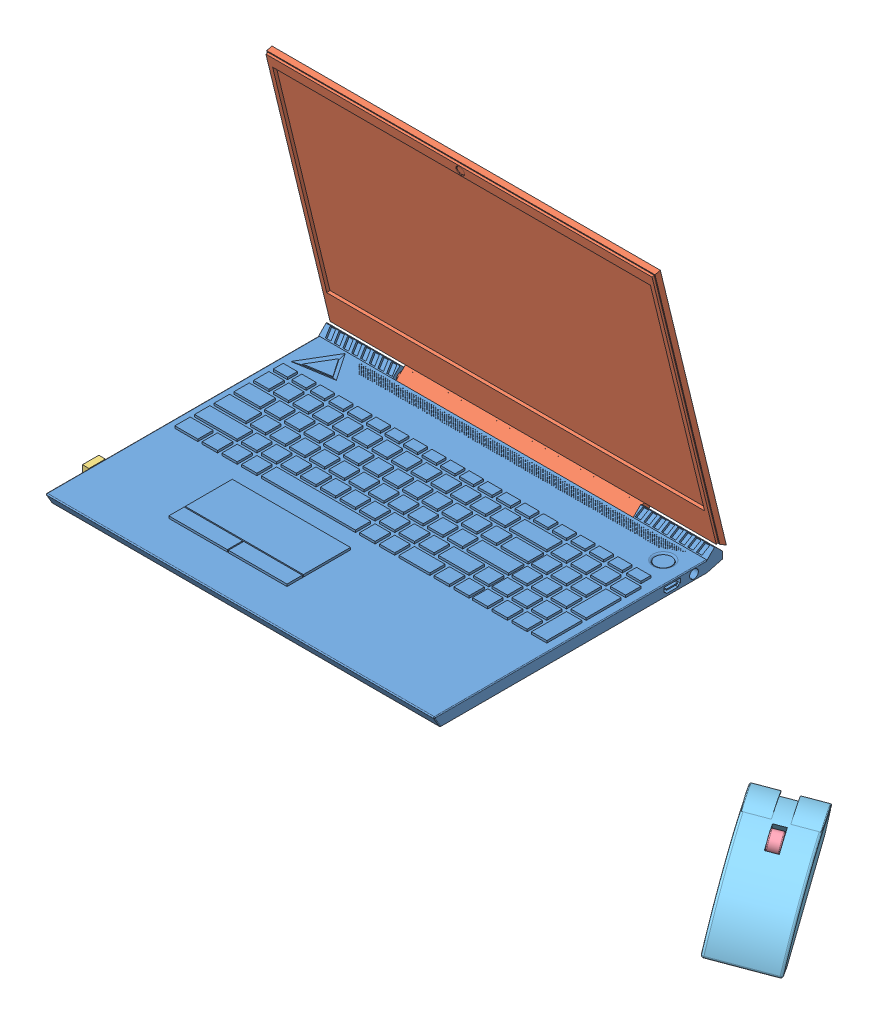
SolidWorks assembly 电脑装配体, configuration Default. Lengths in mm.
Overall size (711.89 292.3 326.41).
5 component instances, 5 part files, 7 mates.
Components (placement in the parent):
- 电脑主机-1: 电脑主机 [默认] at origin size (355 17.07 263.55)
- 电脑屏幕-1: 电脑屏幕 [默认] at (0.5 13.5459 -267.1167) x (1 0 0) z (0 -0.236679 0.971588) size (355 263.33 18.56)
- USB接口-1: USB接口 [默认] at (-179.5 2 -49.5) x (0 0 -1) z (1 0 0) size (15 7 19)
- 鼠标滚轮-1: 鼠标滚轮 [默认] at (467.053 45.3249 -22.9346) x (-0.815257 0.177901 0.551096) z (-0.391516 0.531876 -0.750882) size (10 16 16)
- 鼠标1-1: 鼠标1 [默认] at (438.3721 27.3582 -59.5635) x (-0.815257 0.177901 0.551096) z (-0.421085 0.471183 -0.775032) size (57.22 45.22 124.31)
Mates (geometry in assembly coordinates):
- 重合1: coincident anti-aligned: plane of 电脑主机-1 through (-140 7.7607 -257.6602) normal (1 0 0); plane of 电脑屏幕-1 through (-140 7.7607 -257.6602) normal (-1 0 0)
- 同心1: concentric anti-aligned: cylinder of 电脑主机-1 through (-140 7.7607 -257.6602) axis (1 0 0) radius 4; cylinder of 电脑屏幕-1 through (141 7.7607 -257.6602) axis (-1 0 0) radius 4
- 重合2: coincident anti-aligned: plane of 电脑主机-1 through (-166.5 0 0) normal (-1 0 0); plane of USB接口-1 through (-166.5 2 -55.5) normal (1 0 0)
- 重合3: coincident anti-aligned: plane of 电脑主机-1 through (-166.5 0 -56) normal (0 0 1); plane of USB接口-1 through (-166.5 7 -56) normal (0 0 -1)
- 重合4: coincident anti-aligned: plane of 电脑主机-1 through (-166.5 7.5 0) normal (0 -1 0); plane of USB接口-1 through (-166.5 7.5 -43.5) normal (0 1 0)
- 同心2: concentric aligned: cylinder of 鼠标滚轮-1 through (462.9767 46.2144 -20.1792) axis (0.815257 -0.177901 -0.551096) radius 4; cylinder of 鼠标1-1 through (444.6318 50.2175 -7.7784) axis (0.815257 -0.177901 -0.551096) radius 4
- 重合5: coincident anti-aligned: plane of 鼠标滚轮-1 through (471.1293 44.4354 -25.6901) normal (0.815257 -0.177901 -0.551096); plane of 鼠标1-1 through (471.1685 59.7693 -30.5821) normal (-0.815257 0.177901 0.551096)
